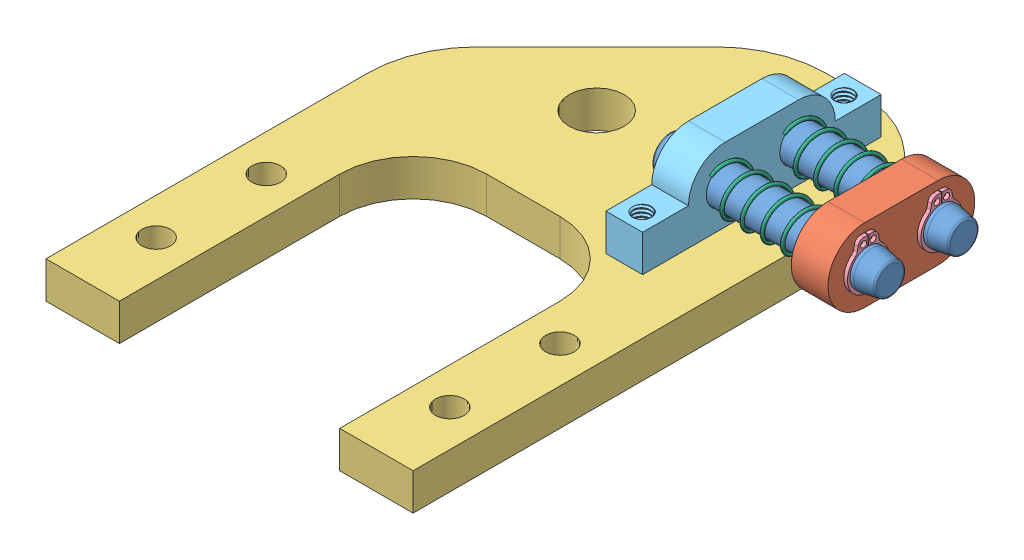
SolidWorks assembly 10011-R01_DROGUE_RELEASE_SYSTEM, configuration Default. Lengths in mm.
Overall size (82.55 19.05 95.25).
13 component instances, 6 part files, 22 mates.
Components (placement in the parent):
- 14057-R01_DROGUE_RELEASE_PIN-1: 14057-R01_DROGUE_RELEASE_PIN [97175A818] at (28.5679 17.8284 20.2643) x (1 0 0) z (0 -0.693989 0.719985) size (38.4 6.35 6.35)
- 14057-R01_DROGUE_RELEASE_PIN-2: 14057-R01_DROGUE_RELEASE_PIN [97175A818] at (28.5679 17.8284 32.9643) x (1 0 0) z (0 -0.480142 0.877191) size (38.4 6.35 6.35)
- 14055-R01_DROGUE_RELEASE_LOWER_SADDLE-1: 14055-R01_DROGUE_RELEASE_LOWER_SADDLE [Default] at (43.1729 17.8284 32.9643) x (0 0 1) z (-1 0 0) size (25.4 12.7 6.35)
- 14054-R01_DROGUE_RELEASE_UPPER-1: 14054-R01_DROGUE_RELEASE_UPPER [Default] at (28.5679 11.4784 96.4643) x (-1 0 0) z (0 -1 0) size (63.5 95.25 6.35)
- 98410A635_EXTERNAL RETAINING RING-1: 98410A635_EXTERNAL RETAINING RING [98410A635] at (12.3754 17.8284 32.9643) x (1 0 0) z (0 -0.251994 0.967729) size (0.64 8.64 7.21)
- 98410A635_EXTERNAL RETAINING RING-2: 98410A635_EXTERNAL RETAINING RING [98410A635] at (12.3754 17.8284 20.2643) size (0.64 8.64 7.21)
- 98410A635_EXTERNAL RETAINING RING-3: 98410A635_EXTERNAL RETAINING RING [98410A635] at (43.4904 17.8284 32.9643) size (0.64 8.64 7.21)
- 98410A635_EXTERNAL RETAINING RING-4: 98410A635_EXTERNAL RETAINING RING [98410A635] at (43.4904 17.8284 20.2643) size (0.64 8.64 7.21)
- 98410A635_EXTERNAL RETAINING RING-5: 98410A635_EXTERNAL RETAINING RING [98410A635] at (36.5054 17.8284 32.9643) x (1 0 0) z (0 0.034463 0.999406) size (0.64 8.64 7.21)
- 98410A635_EXTERNAL RETAINING RING-6: 98410A635_EXTERNAL RETAINING RING [98410A635] at (36.5054 17.8284 20.2643) size (0.64 8.64 7.21)
- 14056-R02_DROGUE_RELEASE_UPPER_SADDLE-1: 14056-R02_DROGUE_RELEASE_UPPER_SADDLE [Default] at (19.0429 11.4784 5.9768) x (0 0 1) z (-1 0 0) size (41.27 12.96 6.35)
- drogue release compression spring-1: drogue release compression spring [Default] at (19.0429 17.8284 32.9643) x (0 0 -1) z (1 0 0) size (7.94 7.94 18.58)
- drogue release compression spring-2: drogue release compression spring [Default] at (19.0429 17.8284 20.2643) x (0 0 -1) z (1 0 0) size (7.94 7.94 18.58)
Mates (geometry in assembly coordinates):
- Coincident4: coincident: plane of 14055-R01_DROGUE_RELEASE_LOWER_SADDLE-1 through (43.1729 17.8284 32.9643) normal (1 0 0); plane of 98410A635_EXTERNAL RETAINING RING-3 through (43.1729 17.8284 32.9643) normal (-1 0 0)
- Coincident5: coincident: plane of 14055-R01_DROGUE_RELEASE_LOWER_SADDLE-1 through (36.8229 17.8284 32.9643) normal (-1 0 0); plane of 98410A635_EXTERNAL RETAINING RING-5 through (36.8229 17.8284 32.9643) normal (1 0 0)
- Coincident6: coincident: plane of 14055-R01_DROGUE_RELEASE_LOWER_SADDLE-1 through (43.1729 17.8284 32.9643) normal (1 0 0); plane of 98410A635_EXTERNAL RETAINING RING-4 through (43.1729 17.8284 20.2643) normal (-1 0 0)
- Coincident7: coincident: plane of 14055-R01_DROGUE_RELEASE_LOWER_SADDLE-1 through (36.8229 17.8284 32.9643) normal (-1 0 0); plane of 98410A635_EXTERNAL RETAINING RING-6 through (36.8229 17.8284 20.2643) normal (1 0 0)
- Concentric14: concentric: cylinder of 14054-R01_DROGUE_RELEASE_UPPER-1 through (15.8679 11.4794 44.0768) axis (0 -1 0) radius 1.397; cylinder of 14056-R02_DROGUE_RELEASE_UPPER_SADDLE-1 through (15.8679 11.4774 44.0768) axis (0 1 0) radius 1.4732
- Concentric15: concentric: cylinder of 14054-R01_DROGUE_RELEASE_UPPER-1 through (15.8679 11.4794 9.1518) axis (0 -1 0) radius 1.397; cylinder of 14056-R02_DROGUE_RELEASE_UPPER_SADDLE-1 through (15.8679 11.4774 9.1518) axis (0 1 0) radius 1.4732
- Coincident9: coincident: plane of 14054-R01_DROGUE_RELEASE_UPPER-1 through (28.5679 11.4784 96.4643) normal (0 1 0); plane of 14056-R02_DROGUE_RELEASE_UPPER_SADDLE-1 through (12.6929 11.4784 5.9768) normal (0 -1 0)
- LimitDistance1: limit distance = 17.78 mm: plane of 14055-R01_DROGUE_RELEASE_LOWER_SADDLE-1 through (36.8229 17.8284 32.9643) normal (-1 0 0); plane of 14056-R02_DROGUE_RELEASE_UPPER_SADDLE-1 through (19.0429 17.8284 20.2643) normal (1 0 0)
- Concentric16: concentric: cylinder of 14057-R01_DROGUE_RELEASE_PIN-2 through (9.5179 17.8284 32.9643) axis (-1 0 0) radius 3.175; cylinder of 14056-R02_DROGUE_RELEASE_UPPER_SADDLE-1 through (12.6929 17.8284 32.9643) axis (1 0 0) radius 3.2639
- Concentric17: concentric: cylinder of 14057-R01_DROGUE_RELEASE_PIN-1 through (9.5179 17.8284 20.2643) axis (-1 0 0) radius 3.175; cylinder of 14056-R02_DROGUE_RELEASE_UPPER_SADDLE-1 through (12.6929 17.8284 20.2643) axis (1 0 0) radius 3.2639
- Concentric18: concentric: cylinder of 14057-R01_DROGUE_RELEASE_PIN-2 through (9.5179 17.8284 32.9643) axis (-1 0 0) radius 3.175; cylinder of 98410A635_EXTERNAL RETAINING RING-1 through (12.6929 17.8284 32.9643) axis (-1 0 0) radius 2.8575
- Concentric19: concentric: cylinder of 14057-R01_DROGUE_RELEASE_PIN-1 through (9.5179 17.8284 20.2643) axis (-1 0 0) radius 3.175; cylinder of 98410A635_EXTERNAL RETAINING RING-2 through (12.6929 17.8284 20.2643) axis (-1 0 0) radius 2.8575
- Distance1: distance = 2.54 mm: plane of 98410A635_EXTERNAL RETAINING RING-1 through (12.0579 17.8284 32.9643) normal (-1 0 0); plane of 14057-R01_DROGUE_RELEASE_PIN-2 through (9.5179 19.6555 33.9643) normal (-1 0 0)
- Distance2: distance = 2.54 mm: plane of 98410A635_EXTERNAL RETAINING RING-2 through (12.0579 17.8284 20.2643) normal (-1 0 0); plane of 14057-R01_DROGUE_RELEASE_PIN-1 through (9.5179 19.328 21.7097) normal (-1 0 0)
- Concentric20: concentric: cylinder of 14057-R01_DROGUE_RELEASE_PIN-2 through (9.5179 17.8284 32.9643) axis (-1 0 0) radius 3.175; cylinder of 14055-R01_DROGUE_RELEASE_LOWER_SADDLE-1 through (36.8229 17.8284 32.9643) axis (1 0 0) radius 3.175
- Concentric21: concentric: cylinder of 14057-R01_DROGUE_RELEASE_PIN-1 through (9.5179 17.8284 20.2643) axis (-1 0 0) radius 3.175; cylinder of 14055-R01_DROGUE_RELEASE_LOWER_SADDLE-1 through (36.8229 17.8284 20.2643) axis (1 0 0) radius 3.175
- Distance3: distance = 3.81 mm: plane of 98410A635_EXTERNAL RETAINING RING-3 through (43.8079 17.8284 32.9643) normal (1 0 0); plane of 14057-R01_DROGUE_RELEASE_PIN-2 through (47.6179 19.8545 34.0732) normal (1 0 0)
- Distance4: distance = 3.81 mm: plane of 98410A635_EXTERNAL RETAINING RING-4 through (43.8079 17.8284 20.2643) normal (1 0 0); plane of 14057-R01_DROGUE_RELEASE_PIN-1 through (47.6179 19.4914 21.8671) normal (1 0 0)
- Concentric22: concentric: cylinder of 14057-R01_DROGUE_RELEASE_PIN-2 through (9.5179 17.8284 32.9643) axis (-1 0 0) radius 3.175; circle of drogue release compression spring-1
- Concentric23: concentric: cylinder of 14057-R01_DROGUE_RELEASE_PIN-1 through (9.5179 17.8284 20.2643) axis (-1 0 0) radius 3.175; circle of drogue release compression spring-2
- Coincident14: coincident: plane of 14056-R02_DROGUE_RELEASE_UPPER_SADDLE-1 through (19.0429 17.8284 20.2643) normal (1 0 0); circle of drogue release compression spring-2
- Coincident15: coincident: plane of 14056-R02_DROGUE_RELEASE_UPPER_SADDLE-1 through (19.0429 17.8284 20.2643) normal (1 0 0); circle of drogue release compression spring-1
